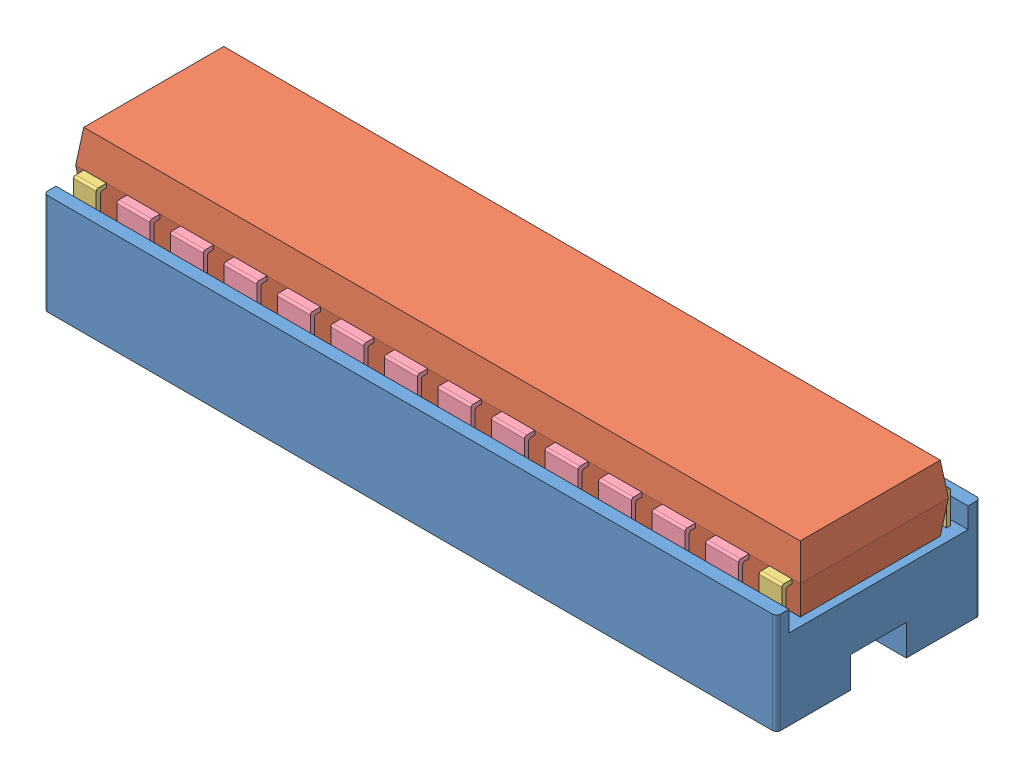
SolidWorks assembly Chip, configuration Défaut. Lengths in mm.
Overall size (35.6 7.1 9.9).
30 component instances, 4 part files, 88 mates.
Components (placement in the parent):
- base chip-1: base chip [Défaut] at (-28.4898 -3.5653 58.5501) size (35.6 4.9 9.9)
- box-1: box [Défaut] at (-28.0898 0.3347 57.0001) size (35.19 3.2 7.19)
- foot (chip)-1: foot (chip) [Défaut] at (-27.8862 -1.0653 57.6966) size (1.1 3 0.5)
- foot (chip)-2: foot (chip) [Défaut] at (5.4138 -1.0653 57.6966) size (1.1 3 0.5)
- foot (big chip)-2: foot (big chip) [Défaut] at (-25.7862 -1.0653 57.6966) size (1.6 3 0.5)
- foot (big chip)-3: foot (big chip) [Défaut] at (-23.1862 -1.0653 57.6966) size (1.6 3 0.5)
- foot (big chip)-4: foot (big chip) [Défaut] at (-20.5862 -1.0653 57.6966) size (1.6 3 0.5)
- foot (big chip)-5: foot (big chip) [Défaut] at (-17.9862 -1.0653 57.6966) size (1.6 3 0.5)
- foot (big chip)-6: foot (big chip) [Défaut] at (-15.3862 -1.0653 57.6966) size (1.6 3 0.5)
- foot (big chip)-7: foot (big chip) [Défaut] at (-12.7862 -1.0653 57.6966) size (1.6 3 0.5)
- foot (big chip)-8: foot (big chip) [Défaut] at (-10.1862 -1.0653 57.6966) size (1.6 3 0.5)
- foot (big chip)-9: foot (big chip) [Défaut] at (-7.5862 -1.0653 57.6966) size (1.6 3 0.5)
- foot (big chip)-10: foot (big chip) [Défaut] at (-4.9862 -1.0653 57.6966) size (1.6 3 0.5)
- foot (big chip)-11: foot (big chip) [Défaut] at (-2.3862 -1.0653 57.6966) size (1.6 3 0.5)
- foot (big chip)-12: foot (big chip) [Défaut] at (0.2138 -1.0653 57.6966) size (1.6 3 0.5)
- foot (big chip)-13: foot (big chip) [Défaut] at (2.8138 -1.0653 57.6966) size (1.6 3 0.5)
- foot (chip)-3: foot (chip) [Défaut] at (6.5138 -1.0653 49.5036) x (-1 0 0) z (0 0 -1) size (1.1 3 0.5)
- foot (big chip)-14: foot (big chip) [Défaut] at (4.4138 -1.0653 49.5036) x (-1 0 0) z (0 0 -1) size (1.6 3 0.5)
- foot (big chip)-15: foot (big chip) [Défaut] at (1.8138 -1.0653 49.5036) x (-1 0 0) z (0 0 -1) size (1.6 3 0.5)
- foot (big chip)-16: foot (big chip) [Défaut] at (-0.7862 -1.0653 49.5036) x (-1 0 0) z (0 0 -1) size (1.6 3 0.5)
- foot (big chip)-17: foot (big chip) [Défaut] at (-3.3862 -1.0653 49.5036) x (-1 0 0) z (0 0 -1) size (1.6 3 0.5)
- foot (big chip)-18: foot (big chip) [Défaut] at (-5.9862 -1.0653 49.5036) x (-1 0 0) z (0 0 -1) size (1.6 3 0.5)
- foot (big chip)-19: foot (big chip) [Défaut] at (-8.5862 -1.0653 49.5036) x (-1 0 0) z (0 0 -1) size (1.6 3 0.5)
- foot (big chip)-20: foot (big chip) [Défaut] at (-11.1862 -1.0653 49.5036) x (-1 0 0) z (0 0 -1) size (1.6 3 0.5)
- foot (big chip)-21: foot (big chip) [Défaut] at (-13.7862 -1.0653 49.5036) x (-1 0 0) z (0 0 -1) size (1.6 3 0.5)
- foot (big chip)-22: foot (big chip) [Défaut] at (-16.3862 -1.0653 49.5036) x (-1 0 0) z (0 0 -1) size (1.6 3 0.5)
- foot (big chip)-23: foot (big chip) [Défaut] at (-18.9862 -1.0653 49.5036) x (-1 0 0) z (0 0 -1) size (1.6 3 0.5)
- foot (big chip)-24: foot (big chip) [Défaut] at (-21.5862 -1.0653 49.5036) x (-1 0 0) z (0 0 -1) size (1.6 3 0.5)
- foot (big chip)-25: foot (big chip) [Défaut] at (-24.1862 -1.0653 49.5036) x (-1 0 0) z (0 0 -1) size (1.6 3 0.5)
- foot (chip)-4: foot (chip) [Défaut] at (-26.7862 -1.0653 49.5036) x (-1 0 0) z (0 0 -1) size (1.1 3 0.5)
Mates (geometry in assembly coordinates):
- Coïncidente1: coincident: plane of base chip-1 through (-28.4898 0.3347 58.5501) normal (0 1 0); plane of box-1 through (-28.0898 0.3347 57.0001) normal (0 -1 0)
- Distance1: distance = 0.95 mm: line of box-1 through (6.7102 0.3347 50.2001) axis (-1 0 0); line of base chip-1 through (-28.4898 0.3347 49.2501) axis (1 0 0)
- Distance2: distance = 0.4 mm: line of box-1 through (-28.0898 0.3347 50.2001) axis (0 0 1); line of base chip-1 through (-28.4898 0.3347 49.2501) axis (0 0 1)
- Coïncidente4: coincident: line of box-1 through (-28.2862 1.9347 57.1966) axis (1 0 0); line of foot (chip)-1 through (-27.8862 1.9347 57.1966) axis (1 0 0)
- Parallèle1: parallel: plane of base chip-1 through (-28.4898 1.3347 57.9501) normal (0 0 -1); plane of foot (chip)-1 through (-27.8862 -1.0653 57.6966) normal (0 0 1)
- Parallèle2: parallel: plane of base chip-1 through (-28.4898 1.3347 57.9501) normal (0 0 -1); plane of foot (big chip)-2 through (-25.7862 -1.0653 57.6966) normal (0 0 1)
- Parallèle3: parallel: plane of base chip-1 through (-28.4898 1.3347 57.9501) normal (0 0 -1); plane of foot (big chip)-3 through (-23.1862 -1.0653 57.4966) normal (0 0 -1)
- Parallèle4: parallel: plane of base chip-1 through (-28.4898 1.3347 57.9501) normal (0 0 -1); plane of foot (big chip)-4 through (-20.5862 -1.0653 57.4966) normal (0 0 -1)
- Parallèle5: parallel: plane of base chip-1 through (-28.4898 1.3347 57.9501) normal (0 0 -1); plane of foot (big chip)-5 through (-17.9862 -1.0653 57.4966) normal (0 0 -1)
- Parallèle6: parallel: plane of base chip-1 through (-28.4898 1.3347 57.9501) normal (0 0 -1); plane of foot (big chip)-6 through (-15.3862 -1.0653 57.4966) normal (0 0 -1)
- Parallèle8: parallel: plane of base chip-1 through (-28.4898 1.3347 57.9501) normal (0 0 -1); plane of foot (big chip)-8 through (-10.1862 -1.0653 57.4966) normal (0 0 -1)
- Parallèle9: parallel: plane of base chip-1 through (-28.4898 1.3347 57.9501) normal (0 0 -1); plane of foot (big chip)-9 through (-7.5862 -1.0653 57.4966) normal (0 0 -1)
- Parallèle10: parallel: plane of base chip-1 through (-28.4898 1.3347 57.9501) normal (0 0 -1); plane of foot (big chip)-10 through (-4.9862 -1.0653 57.4966) normal (0 0 -1)
- Parallèle11: parallel: plane of base chip-1 through (-28.4898 1.3347 57.9501) normal (0 0 -1); plane of foot (big chip)-10 through (-4.9862 -1.0653 57.4966) normal (0 0 -1)
- Parallèle12: parallel: plane of base chip-1 through (-28.4898 1.3347 57.9501) normal (0 0 -1); plane of foot (big chip)-11 through (-2.3862 -1.0653 57.4966) normal (0 0 -1)
- Parallèle13: parallel: plane of base chip-1 through (-28.4898 1.3347 57.9501) normal (0 0 -1); plane of foot (big chip)-13 through (2.8138 -1.0653 57.4966) normal (0 0 -1)
- Coïncidente19: coincident: line of box-1 through (-28.2862 1.9347 57.1966) axis (1 0 0); line of foot (big chip)-2 through (-25.7862 1.9347 57.1966) axis (1 0 0)
- Coïncidente20: coincident: line of box-1 through (-28.2862 1.9347 57.1966) axis (1 0 0); line of foot (big chip)-3 through (-23.1862 1.9347 57.1966) axis (1 0 0)
- Coïncidente21: coincident: line of box-1 through (-28.2862 1.9347 57.1966) axis (1 0 0); line of foot (big chip)-4 through (-20.5862 1.9347 57.1966) axis (1 0 0)
- Coïncidente22: coincident: line of box-1 through (-28.2862 1.9347 57.1966) axis (1 0 0); line of foot (big chip)-5 through (-17.9862 1.9347 57.1966) axis (1 0 0)
- Coïncidente23: coincident: line of box-1 through (-28.2862 1.9347 57.1966) axis (1 0 0); line of foot (big chip)-6 through (-15.3862 1.9347 57.1966) axis (1 0 0)
- Coïncidente24: coincident: line of box-1 through (-28.2862 1.9347 57.1966) axis (1 0 0); line of foot (big chip)-7 through (-12.7862 1.9347 57.1966) axis (1 0 0)
- Coïncidente25: coincident: line of box-1 through (-28.2862 1.9347 57.1966) axis (1 0 0); line of foot (big chip)-8 through (-10.1862 1.9347 57.1966) axis (1 0 0)
- Coïncidente26: coincident: line of box-1 through (-28.2862 1.9347 57.1966) axis (1 0 0); line of foot (big chip)-9 through (-7.5862 1.9347 57.1966) axis (1 0 0)
- Coïncidente27: coincident: line of box-1 through (-28.2862 1.9347 57.1966) axis (1 0 0); line of foot (big chip)-10 through (-4.9862 1.9347 57.1966) axis (1 0 0)
- Coïncidente28: coincident: line of box-1 through (-28.2862 1.9347 57.1966) axis (1 0 0); line of foot (big chip)-11 through (-2.3862 1.9347 57.1966) axis (1 0 0)
- Coïncidente29: coincident: line of box-1 through (-28.2862 1.9347 57.1966) axis (1 0 0); line of foot (big chip)-12 through (0.2138 1.9347 57.1966) axis (1 0 0)
- Coïncidente30: coincident: line of box-1 through (-28.2862 1.9347 57.1966) axis (1 0 0); line of foot (big chip)-13 through (2.8138 1.9347 57.1966) axis (1 0 0)
- Coïncidente31: coincident: line of box-1 through (-28.2862 1.9347 57.1966) axis (1 0 0); line of foot (chip)-2 through (5.4138 1.9347 57.1966) axis (1 0 0)
- Parallèle14: parallel: plane of base chip-1 through (-28.4898 1.3347 57.9501) normal (0 0 -1); plane of foot (big chip)-12 through (0.2138 -1.0653 57.6966) normal (0 0 1)
- Distance3: distance = 0.4 mm: line of foot (chip)-1 through (-27.8862 1.9347 57.1966) axis (0 0 1); point of box-1
- Distance4: distance = 1 mm: line of foot (chip)-1 through (-26.7862 1.9347 57.1966) axis (0 0 1); line of foot (big chip)-2 through (-25.7862 1.9347 57.1966) axis (0 0 1)
- Distance5: distance = 1 mm: line of foot (big chip)-2 through (-24.1862 1.9347 57.1966) axis (0 0 1); line of foot (big chip)-3 through (-23.1862 1.9347 57.1966) axis (0 0 1)
- Distance6: distance = 1 mm: line of foot (big chip)-3 through (-21.5862 1.9347 57.1966) axis (0 0 1); line of foot (big chip)-4 through (-20.5862 1.9347 57.1966) axis (0 0 1)
- Distance7: distance = 1 mm: line of foot (big chip)-5 through (-17.9862 1.9347 57.1966) axis (0 0 1); line of foot (big chip)-4 through (-18.9862 1.9347 57.1966) axis (0 0 1)
- Distance8: distance = 1 mm: line of foot (big chip)-5 through (-16.3862 1.9347 57.1966) axis (0 0 1); line of foot (big chip)-6 through (-15.3862 1.9347 57.1966) axis (0 0 1)
- Distance9: distance = 1 mm: line of foot (big chip)-6 through (-13.7862 1.9347 57.1966) axis (0 0 1); line of foot (big chip)-7 through (-12.7862 1.9347 57.1966) axis (0 0 1)
- Distance10: distance = 1 mm: line of foot (big chip)-7 through (-11.1862 1.9347 57.1966) axis (0 0 1); line of foot (big chip)-8 through (-10.1862 1.9347 57.1966) axis (0 0 1)
- Distance11: distance = 1 mm: line of foot (big chip)-8 through (-8.5862 1.9347 57.1966) axis (0 0 1); line of foot (big chip)-9 through (-7.5862 1.9347 57.1966) axis (0 0 1)
- Distance12: distance = 1 mm: line of foot (big chip)-9 through (-5.9862 1.9347 57.1966) axis (0 0 1); line of foot (big chip)-10 through (-4.9862 1.9347 57.1966) axis (0 0 1)
- Distance13: distance = 1 mm: line of foot (big chip)-10 through (-3.3862 1.9347 57.1966) axis (0 0 1); line of foot (big chip)-11 through (-2.3862 1.9347 57.1966) axis (0 0 1)
- Distance14: distance = 1 mm: line of foot (big chip)-11 through (-0.7862 1.9347 57.1966) axis (0 0 1); line of foot (big chip)-12 through (0.2138 1.9347 57.1966) axis (0 0 1)
- Distance15: distance = 1 mm: line of foot (big chip)-12 through (1.8138 1.9347 57.1966) axis (0 0 1); line of foot (big chip)-13 through (2.8138 1.9347 57.1966) axis (0 0 1)
- Distance16: distance = 1 mm: line of foot (big chip)-13 through (4.4138 1.9347 57.1966) axis (0 0 1); line of foot (chip)-2 through (5.4138 1.9347 57.1966) axis (0 0 1)
- Parallèle15: parallel: plane of base chip-1 through (-28.4898 0.3347 48.6501) normal (0 0 -1); plane of foot (chip)-3 through (6.5138 -1.0653 49.5036) normal (0 0 -1)
- Parallèle16: parallel: plane of base chip-1 through (-28.4898 0.3347 48.6501) normal (0 0 -1); plane of foot (big chip)-14 through (4.4138 -1.0653 49.5036) normal (0 0 -1)
- Parallèle17: parallel: plane of base chip-1 through (-28.4898 0.3347 48.6501) normal (0 0 -1); plane of foot (big chip)-15 through (1.8138 -1.0653 49.5036) normal (0 0 -1)
- Parallèle18: parallel: plane of base chip-1 through (-28.4898 0.3347 48.6501) normal (0 0 -1); plane of foot (big chip)-16 through (-0.7862 -1.0653 49.5036) normal (0 0 -1)
- Parallèle19: parallel: plane of base chip-1 through (-28.4898 0.3347 48.6501) normal (0 0 -1); plane of foot (big chip)-17 through (-3.3862 -1.0653 49.5036) normal (0 0 -1)
- Parallèle20: parallel: plane of base chip-1 through (-28.4898 0.3347 48.6501) normal (0 0 -1); plane of foot (big chip)-18 through (-5.9862 -1.0653 49.5036) normal (0 0 -1)
- Parallèle21: parallel: plane of base chip-1 through (-28.4898 0.3347 48.6501) normal (0 0 -1); plane of foot (big chip)-19 through (-8.5862 -1.0653 49.5036) normal (0 0 -1)
- Parallèle22: parallel: plane of base chip-1 through (-28.4898 0.3347 48.6501) normal (0 0 -1); plane of foot (big chip)-20 through (-11.1862 -1.0653 49.5036) normal (0 0 -1)
- Parallèle23: parallel: plane of base chip-1 through (-28.4898 0.3347 48.6501) normal (0 0 -1); plane of foot (big chip)-21 through (-13.7862 -1.0653 49.5036) normal (0 0 -1)
- Parallèle24: parallel: plane of base chip-1 through (-28.4898 0.3347 48.6501) normal (0 0 -1); plane of foot (big chip)-22 through (-16.3862 -1.0653 49.5036) normal (0 0 -1)
- Parallèle25: parallel: plane of base chip-1 through (-28.4898 0.3347 48.6501) normal (0 0 -1); plane of foot (big chip)-23 through (-18.9862 -1.0653 49.5036) normal (0 0 -1)
- Parallèle26: parallel: plane of base chip-1 through (-28.4898 0.3347 48.6501) normal (0 0 -1); plane of foot (big chip)-24 through (-21.5862 -1.0653 49.5036) normal (0 0 -1)
- Parallèle27: parallel: plane of base chip-1 through (-28.4898 0.3347 48.6501) normal (0 0 -1); plane of foot (big chip)-25 through (-24.1862 -1.0653 49.5036) normal (0 0 -1)
- Parallèle28: parallel: plane of base chip-1 through (-28.4898 0.3347 48.6501) normal (0 0 -1); plane of foot (chip)-4 through (-26.7862 -1.0653 49.5036) normal (0 0 -1)
- Coïncidente60: coincident: line of box-1 through (6.9067 1.9347 50.0036) axis (-1 0 0); line of foot (chip)-4 through (-26.7862 1.9347 50.0036) axis (-1 0 0)
- Parallèle29: parallel: plane of base chip-1 through (-28.4898 1.3347 57.9501) normal (0 0 -1); plane of foot (chip)-2 through (5.4138 -1.0653 57.6966) normal (0 0 1)
- Parallèle30: parallel: plane of base chip-1 through (-28.4898 1.3347 57.9501) normal (0 0 -1); plane of foot (big chip)-7 through (-12.7862 -1.0653 57.6966) normal (0 0 1)
- Coïncidente72: coincident: line of box-1 through (6.9067 1.9347 50.0036) axis (-1 0 0); line of foot (big chip)-25 through (-24.1862 1.9347 50.0036) axis (-1 0 0)
- Coïncidente73: coincident: line of box-1 through (6.9067 1.9347 50.0036) axis (-1 0 0); line of foot (big chip)-24 through (-21.5862 1.9347 50.0036) axis (-1 0 0)
- Coïncidente74: coincident: line of box-1 through (6.9067 1.9347 50.0036) axis (-1 0 0); line of foot (big chip)-23 through (-18.9862 1.9347 50.0036) axis (-1 0 0)
- Coïncidente75: coincident: line of box-1 through (6.9067 1.9347 50.0036) axis (-1 0 0); line of foot (big chip)-22 through (-16.3862 1.9347 50.0036) axis (-1 0 0)
- Coïncidente76: coincident: line of box-1 through (6.9067 1.9347 50.0036) axis (-1 0 0); line of foot (big chip)-21 through (-13.7862 1.9347 50.0036) axis (-1 0 0)
- Coïncidente77: coincident: line of box-1 through (6.9067 1.9347 50.0036) axis (-1 0 0); line of foot (big chip)-20 through (-11.1862 1.9347 50.0036) axis (-1 0 0)
- Coïncidente78: coincident: line of box-1 through (6.9067 1.9347 50.0036) axis (-1 0 0); line of foot (big chip)-19 through (-8.5862 1.9347 50.0036) axis (-1 0 0)
- Coïncidente79: coincident: line of box-1 through (6.9067 1.9347 50.0036) axis (-1 0 0); line of foot (big chip)-18 through (-5.9862 1.9347 50.0036) axis (-1 0 0)
- Coïncidente80: coincident: line of box-1 through (6.9067 1.9347 50.0036) axis (-1 0 0); line of foot (big chip)-17 through (-3.3862 1.9347 50.0036) axis (-1 0 0)
- Coïncidente81: coincident: line of box-1 through (6.9067 1.9347 50.0036) axis (-1 0 0); line of foot (big chip)-16 through (-0.7862 1.9347 50.0036) axis (-1 0 0)
- Coïncidente82: coincident: line of box-1 through (6.9067 1.9347 50.0036) axis (-1 0 0); line of foot (big chip)-15 through (1.8138 1.9347 50.0036) axis (-1 0 0)
- Coïncidente83: coincident: line of box-1 through (6.9067 1.9347 50.0036) axis (-1 0 0); line of foot (big chip)-14 through (4.4138 1.9347 50.0036) axis (-1 0 0)
- Coïncidente84: coincident: line of box-1 through (6.9067 1.9347 50.0036) axis (-1 0 0); line of foot (chip)-3 through (6.5138 1.9347 50.0036) axis (-1 0 0)
- Distance18: distance = 1 mm: line of foot (chip)-3 through (5.4138 1.9347 50.0036) axis (0 0 -1); line of foot (big chip)-14 through (4.4138 1.9347 50.0036) axis (0 0 -1)
- Distance19: distance = 1 mm: line of foot (big chip)-14 through (2.8138 1.9347 50.0036) axis (0 0 -1); line of foot (big chip)-15 through (1.8138 1.9347 50.0036) axis (0 0 -1)
- Distance20: distance = 1 mm: line of foot (big chip)-15 through (0.2138 1.9347 50.0036) axis (0 0 -1); line of foot (big chip)-16 through (-0.7862 1.9347 50.0036) axis (0 0 -1)
- Distance21: distance = 1 mm: line of foot (big chip)-16 through (-2.3862 1.9347 50.0036) axis (0 0 -1); line of foot (big chip)-17 through (-3.3862 1.9347 50.0036) axis (0 0 -1)
- Distance22: distance = 1 mm: line of foot (big chip)-17 through (-4.9862 1.9347 50.0036) axis (0 0 -1); line of foot (big chip)-18 through (-5.9862 1.9347 50.0036) axis (0 0 -1)
- Distance23: distance = 1 mm: line of foot (big chip)-19 through (-8.5862 1.9347 50.0036) axis (0 0 -1); line of foot (big chip)-18 through (-7.5862 1.9347 50.0036) axis (0 0 -1)
- Distance24: distance = 1 mm: line of foot (big chip)-20 through (-11.1862 1.9347 50.0036) axis (0 0 -1); line of foot (big chip)-19 through (-10.1862 1.9347 50.0036) axis (0 0 -1)
- Distance25: distance = 1 mm: line of foot (big chip)-21 through (-13.7862 1.9347 50.0036) axis (0 0 -1); line of foot (big chip)-20 through (-12.7862 1.9347 50.0036) axis (0 0 -1)
- Distance26: distance = 1 mm: line of foot (big chip)-21 through (-15.3862 1.9347 50.0036) axis (0 0 -1); line of foot (big chip)-22 through (-16.3862 1.9347 50.0036) axis (0 0 -1)
- Distance27: distance = 1 mm: line of foot (big chip)-22 through (-17.9862 1.9347 50.0036) axis (0 0 -1); line of foot (big chip)-23 through (-18.9862 1.9347 50.0036) axis (0 0 -1)
- Distance28: distance = 1 mm: line of foot (big chip)-23 through (-20.5862 1.9347 50.0036) axis (0 0 -1); line of foot (big chip)-24 through (-21.5862 1.9347 50.0036) axis (0 0 -1)
- Distance29: distance = 1 mm: line of foot (big chip)-24 through (-23.1862 1.9347 50.0036) axis (0 0 -1); line of foot (big chip)-25 through (-24.1862 1.9347 50.0036) axis (0 0 -1)
- Distance30: distance = 1 mm: line of foot (big chip)-25 through (-25.7862 1.9347 50.0036) axis (0 0 -1); line of foot (chip)-4 through (-26.7862 1.9347 50.0036) axis (0 0 -1)
- Distance31: distance = 0.4 mm: line of foot (chip)-4 through (-27.8862 1.9347 50.0036) axis (0 0 -1); point of box-1
